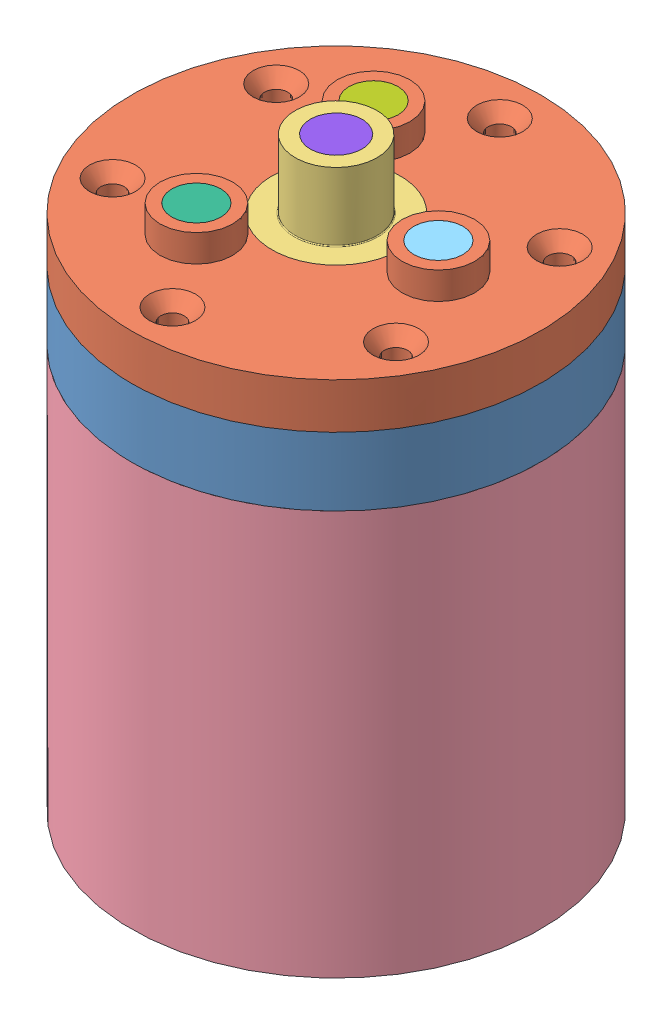
SolidWorks assembly Assembly_Pintle_V3, configuration Default. Lengths in mm.
Overall size (146.34 163.8 146.34).
8 component instances, 8 part files, 12 mates.
Components (placement in the parent):
- Part_annulus_base_v3-1: Part_annulus_base_v3 [Default] at (38.7851 49.7212 96.5266) size (114.3 19.05 114.3)
- Part_V3_Top_Plate-1: Part_V3_Top_Plate [Default] at (38.7851 68.7712 96.5266) size (114.3 20.32 114.3)
- Part_V3_Pintle-1: Part_V3_Pintle [Default] at (38.7851 45.6924 96.5266) x (0.558314 0 -0.82963) z (0.82963 0 0.558314) size (35.81 65.4 35.81)
- Outlet_Lid_For_Sim-3: Outlet_Lid_For_Sim [Default] at (38.7851 -63.2788 96.5266) x (0.940507 0 -0.339775) z (0.339775 0 0.940507) size (114.3 113 114.3)
- LID1-1: LID1 [Default] at origin size (14.11 1.16 14.11)
- LID2-1: LID2 [Default] at origin size (14.11 1.16 14.11)
- LID3-1: LID3 [Default] at origin size (14.11 1.16 14.11)
- LID4-1: LID4 [Default] at origin size (14.9 1.16 14.9)
Mates (geometry in assembly coordinates):
- Concentric1: concentric aligned: cylinder of Part_annulus_base_v3-1 through (38.7851 68.7712 96.5266) axis (0 -1 0) radius 57.15; cylinder of Part_V3_Top_Plate-1 through (38.7851 75.1212 96.5266) axis (0 -1 0) radius 57.15
- Concentric14: concentric aligned: cylinder of Part_annulus_base_v3-1 through (78.3798 68.7712 119.3866) axis (0 1 0) radius 2.5527; cylinder of Part_V3_Top_Plate-1 through (78.3798 81.4712 119.3866) axis (0 1 0) radius 3.2639
- Coincident1: coincident anti-aligned: plane of Part_annulus_base_v3-1 through (38.7851 68.7712 96.5266) normal (0 1 0); plane of Part_V3_Top_Plate-1 through (38.7851 68.7712 96.5266) normal (0 -1 0)
- Concentric15: concentric aligned: cylinder of Part_V3_Top_Plate-1 through (38.7851 81.4712 96.5266) axis (0 -1 0) radius 17.653; cylinder of Part_V3_Pintle-1 through (38.7851 81.4712 96.5266) axis (0 -1 0) radius 17.907
- Coincident2: coincident anti-aligned: plane of Part_V3_Top_Plate-1 through (38.7851 75.1212 96.5266) normal (0 1 0); plane of Part_V3_Pintle-1 through (38.7851 75.1212 96.5266) normal (0 -1 0)
- Concentric16: concentric anti-aligned: cylinder of Part_V3_Top_Plate-1 through (-0.8095 81.4712 119.3866) axis (0 1 0) radius 3.2639; cylinder of ? through (-0.8095 66.3558 119.3866) axis (0 -1 0) radius 3.175
- Coincident3: coincident aligned: cone of Part_V3_Top_Plate-1 through (-0.8095 81.4712 119.3866) axis (0 -1 0); cylinder of ? through (-0.8095 78.1414 119.3866) axis (0 -1 0) radius 715.585
- Concentric19: concentric anti-aligned: cylinder of Part_V3_Top_Plate-1 through (78.3798 81.4712 73.6666) axis (0 1 0) radius 3.2639; cylinder of ? through (78.3798 63.1808 73.6666) axis (0 -1 0) radius 3.175
- Coincident4: coincident aligned: cylinder of Part_V3_Top_Plate-1 through (78.3798 81.4712 73.6666) axis (0 -1 0) radius 715.585; cylinder of ? through (78.3798 78.1414 73.6666) axis (0 -1 0) radius 715.585
- Concentric20: concentric: cylinder of Part_V3_Top_Plate-1 through (-0.8095 81.4712 119.3866) axis (0 1 0) radius 3.2639; cylinder of ? through (-0.8095 60.0058 119.3866) axis (0 -1 0) radius 3.175
- Coincident5: coincident aligned: cylinder of Part_V3_Top_Plate-1 through (-0.8095 81.4712 119.3866) axis (0 -1 0) radius 715.585; cylinder of ? through (-0.8095 78.1414 119.3866) axis (0 -1 0) radius 715.585
- Coincident8: coincident aligned: circle of Part_annulus_base_v3-1; circle of Outlet_Lid_For_Sim-3
